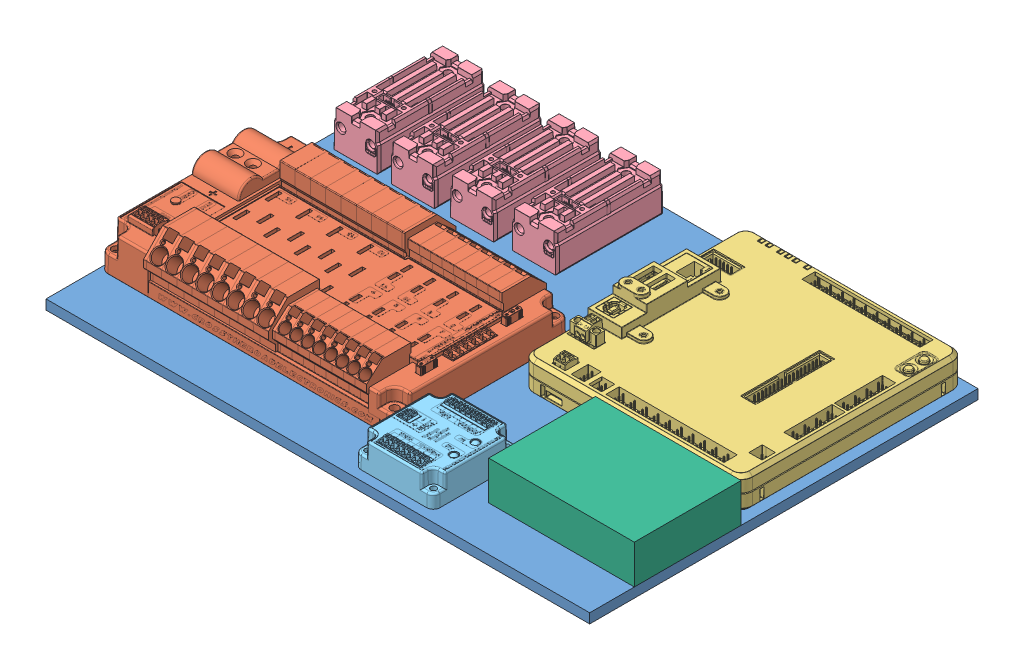
SolidWorks assembly Intial concept(14x10), configuration Default. Lengths in mm.
Overall size (355.6 43.11 254).
9 component instances, 6 part files, 27 mates.
Components (placement in the parent):
- intial concept poly (14x10)-1: intial concept poly (14x10) [Default] at (-62.4994 167.7714 419.0899) size (355.6 6.35 254)
- PDP-1: PDP [Default] at (39.1796 180.8016 327.3621) size (192.68 36.15 120.93)
- Roborio-1: Roborio [Default] at (216.4307 183.7734 241.9757) x (0 0 -1) z (0 1 0) size (146.27 143.19 36.83)
- Speed Controller-1: Speed Controller [Default] at (-38.7557 189.9589 205.2974) x (1 0 0) z (0 -1 0) size (30.12 70.11 24.39)
- Speed Controller-2: Speed Controller [Default] at (-0.5553 189.9589 206.1129) x (1 0 0) z (0 -1 0) size (30.12 70.11 24.39)
- Speed Controller-3: Speed Controller [Default] at (37.7211 189.9589 205.6322) x (1 0 0) z (0 -1 0) size (30.12 70.11 24.39)
- Speed Controller-4: Speed Controller [Default] at (76.7154 189.9589 204.1553) x (1 0 0) z (0 -1 0) size (30.12 70.11 24.39)
- VRM-1: VRM [Default] at (160.7634 181.2527 385.1968) x (0 0 1) z (-1 0 0) size (56.39 19.92 51.56)
- radio b;ock-1: radio b;ock [Default] at (293.1006 174.1214 389.8799) x (0 0 -1) z (1 0 0) size (69.85 25.4 95.25)
Mates (geometry in assembly coordinates):
- Coincident3: coincident aligned: plane of intial concept poly (14x10)-1 through (-62.4994 174.1214 419.0899) normal (0 1 0); plane of Roborio-1 through (288.3973 174.1214 315.4877) normal (0 1 0)
- Parallel1: parallel anti-aligned: plane of intial concept poly (14x10)-1 through (293.1006 174.1214 419.0899) normal (1 0 0); plane of Roborio-1 through (288.0206 176.3535 310.0498) normal (-1 0 0)
- Distance1: distance = 3.81 mm anti-aligned: plane of intial concept poly (14x10)-1 through (-62.4994 174.1214 165.0899) normal (0 0 -1); plane of Roborio-1 through (282.9594 176.3535 168.8999) normal (0 0 1)
- Distance4: distance = 5.08 mm anti-aligned: plane of Roborio-1 through (288.0206 176.3535 310.0498) normal (-1 0 0); plane of intial concept poly (14x10)-1 through (293.1006 174.1214 419.0899) normal (1 0 0)
- Coincident15: coincident anti-aligned: plane of intial concept poly (14x10)-1 through (-62.4994 174.1214 419.0899) normal (0 1 0); plane of Speed Controller-1 through (-23.6934 174.1214 170.3724) normal (0 -1 0)
- Coincident19: coincident anti-aligned: plane of intial concept poly (14x10)-1 through (-62.4994 174.1214 419.0899) normal (0 1 0); plane of Speed Controller-2 through (14.5071 174.1214 171.1879) normal (0 -1 0)
- Coincident20: coincident anti-aligned: plane of intial concept poly (14x10)-1 through (-62.4994 174.1214 419.0899) normal (0 1 0); plane of Speed Controller-4 through (91.7777 174.1214 169.2303) normal (0 -1 0)
- Coincident21: coincident anti-aligned: plane of intial concept poly (14x10)-1 through (-62.4994 174.1214 419.0899) normal (0 1 0); plane of Speed Controller-3 through (52.7834 174.1214 170.7072) normal (0 -1 0)
- Coincident23: coincident anti-aligned: plane of intial concept poly (14x10)-1 through (-62.4994 174.1214 419.0899) normal (0 1 0); plane of PDP-1 through (-56.2736 174.1214 275.1651) normal (0 -1 0)
- Distance12: distance = 34.29 mm aligned: plane of PDP-1 through (-28.2094 187.4345 270.9293) normal (-1 0 0); plane of intial concept poly (14x10)-1 through (-62.4994 174.1214 419.0899) normal (-1 0 0)
- Distance15: distance = 50.8 mm aligned: plane of PDP-1 through (-52.8332 204.6632 368.2899) normal (0 0 1); plane of intial concept poly (14x10)-1 through (-62.4994 174.1214 419.0899) normal (0 0 1)
- Distance16: distance = 53.6981 mm aligned: plane of intial concept poly (14x10)-1 through (-62.4994 174.1214 165.0899) normal (0 0 -1); plane of Speed Controller-1 through (-36.3757 196.6089 218.788) normal (0 0 -1)
- Distance17: distance = 23.5837 mm aligned: plane of intial concept poly (14x10)-1 through (-62.4994 174.1214 419.0899) normal (-1 0 0); plane of Speed Controller-1 through (-38.9157 196.6089 219.188) normal (-1 0 0)
- Distance18: distance = 64.3241 mm aligned: plane of Speed Controller-2 through (1.8247 196.6089 220.0035) normal (-1 0 0); plane of intial concept poly (14x10)-1 through (-62.4994 174.1214 419.0899) normal (-1 0 0)
- Distance19: distance = 54.5135 mm aligned: plane of intial concept poly (14x10)-1 through (-62.4994 174.1214 165.0899) normal (0 0 -1); plane of Speed Controller-2 through (0.5547 196.6089 219.6035) normal (0 0 -1)
- Distance20: distance = 54.0329 mm aligned: plane of Speed Controller-3 through (40.1011 196.6089 219.1228) normal (0 0 -1); plane of intial concept poly (14x10)-1 through (-62.4994 174.1214 165.0899) normal (0 0 -1)
- Distance21: distance = 98.7905 mm: plane of Speed Controller-3 through (36.2911 196.6089 219.5228) normal (-1 0 0); line of intial concept poly (14x10)-1 through (-62.4994 174.1214 165.0899) axis (0 0 1)
- Distance22: distance = 52.5559 mm: line of intial concept poly (14x10)-1 through (293.1006 174.1214 165.0899) axis (-1 0 0); plane of Speed Controller-4 through (79.0954 196.6089 217.6459) normal (0 0 -1)
- Distance23: distance = 141.5948 mm: line of Speed Controller-4 through (79.0954 196.6089 218.0459) axis (0 -1 0); plane of intial concept poly (14x10)-1 through (-62.4994 174.1214 419.0899) normal (-1 0 0)
- Coincident40: coincident anti-aligned: plane of intial concept poly (14x10)-1 through (-62.4994 174.1214 419.0899) normal (0 1 0); plane of VRM-1 through (180.3107 174.1214 408.5411) normal (0 -1 0)
- Parallel24: parallel aligned: plane of intial concept poly (14x10)-1 through (-62.4994 174.1214 419.0899) normal (0 0 1); plane of VRM-1 through (145.2706 194.046 406.3899) normal (0 0 1)
- Distance24: distance = 12.7 mm aligned: plane of VRM-1 through (148.7706 194.046 406.3899) normal (0 0 1); plane of intial concept poly (14x10)-1 through (-62.4994 174.1214 419.0899) normal (0 0 1)
- Distance25: distance = 120.65 mm aligned: plane of VRM-1 through (172.4506 194.046 406.3899) normal (1 0 0); plane of intial concept poly (14x10)-1 through (293.1006 174.1214 419.0899) normal (1 0 0)
- Coincident46: coincident anti-aligned: plane of intial concept poly (14x10)-1 through (-62.4994 174.1214 419.0899) normal (0 1 0); plane of radio b;ock-1 through (293.1006 174.1214 389.8799) normal (0 -1 0)
- Perpendicular3: perpendicular: plane of intial concept poly (14x10)-1 through (-62.4994 174.1214 419.0899) normal (0 0 1); plane of radio b;ock-1 through (293.1006 199.5214 389.8799) normal (1 0 0)
- Distance26: distance = 29.21 mm aligned: plane of radio b;ock-1 through (293.1006 199.5214 389.8799) normal (0 0 1); plane of intial concept poly (14x10)-1 through (-62.4994 174.1214 419.0899) normal (0 0 1)
- Coincident48: coincident aligned: plane of intial concept poly (14x10)-1 through (293.1006 174.1214 419.0899) normal (1 0 0); plane of radio b;ock-1 through (293.1006 199.5214 389.8799) normal (1 0 0)
